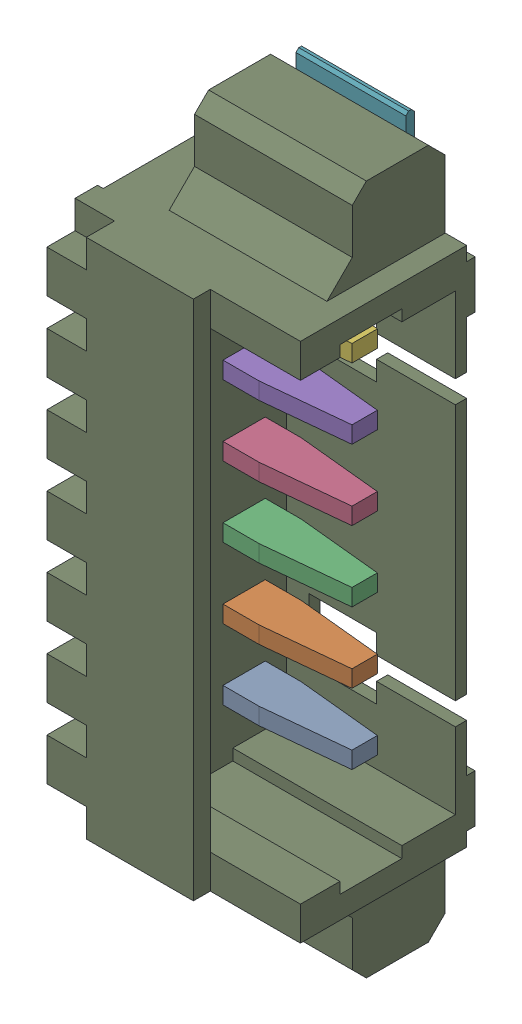
SolidWorks assembly J6, configuration Default. Lengths in mm.
Overall size (5.4 12.25 3.41).
10 component instances, 3 part files, 0 mates.
Components (placement in the parent):
- 653106131822-1: 653106131822 [Default] at (117.4 16.2249 1.69) x (0 1 0) z (0 0 1) size (12.25 5.4 3.41)
  - 6531xx131822_PIN-1: 6531xx131822_PIN [Default] at (-3.125 2.7 -0.425) x (1 0 0) z (0 -1 0) size (0.3 1.48 4.54)
  - 6531xx131822_PIN-2: 6531xx131822_PIN [Default] at (-1.875 2.7 -0.425) x (1 0 0) z (0 -1 0) size (0.3 1.48 4.54)
  - 6531xx131822_PIN-3: 6531xx131822_PIN [Default] at (-0.625 2.7 -0.425) x (1 0 0) z (0 -1 0) size (0.3 1.48 4.54)
  - 6531xx131822_PIN-4: 6531xx131822_PIN [Default] at (0.625 2.7 -0.425) x (1 0 0) z (0 -1 0) size (0.3 1.48 4.54)
  - 6531xx131822_PIN-5: 6531xx131822_PIN [Default] at (1.875 2.7 -0.425) x (1 0 0) z (0 -1 0) size (0.3 1.48 4.54)
  - 6531xx131822_PIN-6: 6531xx131822_PIN [Default] at (3.125 2.7 -0.425) x (1 0 0) z (0 -1 0) size (0.3 1.48 4.54)
  - 6531xx131822_PIN_FLANGE-1: 6531xx131822_PIN_FLANGE [Default] at (5 -0.045 -1.05) size (1.25 1.95 1.4)
  - 6531xx131822_PIN_FLANGE-2: 6531xx131822_PIN_FLANGE [Default] at (-5 -0.045 -1.05) x (-1 0 0) z (0 0 1) size (1.25 1.95 1.4)
  - 653106131822-1: 653106131822 [Default] at origin size (12.25 4.2 3.4)
